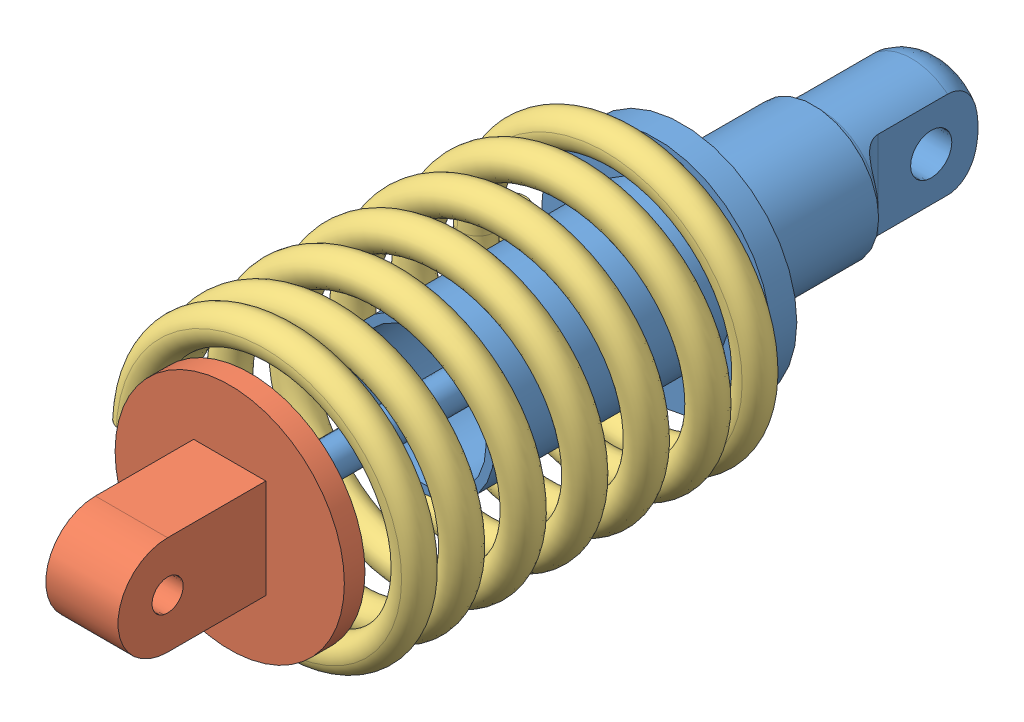
SolidWorks assembly coilover, configuration Default. Lengths in mm.
Overall size (63.59 63.59 167.73).
3 component instances, 3 part files, 4 mates.
Components (placement in the parent):
- coilover base-1: coilover base [Default] at (-107.9256 24.6681 -16.3782) size (44.45 44.45 139.07)
- coilover end-1: coilover end [Default] at (-100.9256 24.6681 115.8118) x (0 -1 0) z (-1 0 0) size (44.45 32.67 44.45)
- coil-1: coil [Default] at (-107.9256 24.6681 23.5385) size (63.59 63.59 79.45)
Mates (geometry in assembly coordinates):
- Concentric1: concentric aligned: cylinder of coilover base-1 through (-107.9256 24.6681 96.7618) axis (0 0 -1) radius 3.175; cylinder of coilover end-1 through (-107.9256 24.6681 96.7618) axis (0 0 -1) radius 3.175
- Coincident1: coincident anti-aligned: plane of coilover base-1 through (-107.9256 24.6681 96.7618) normal (0 0 1); plane of coilover end-1 through (-100.9256 24.6681 96.7618) normal (0 0 -1)
- Concentric3: concentric anti-aligned: circle of coil-1; cylinder of coilover base-1 through (-107.9256 24.6681 59.7418) axis (0 0 -1) radius 14.2875
- Coincident3: coincident aligned: plane of coilover base-1 through (-114.9256 11.9681 -16.3782) normal (-1 0 0); plane of coilover end-1 through (-114.9256 24.6681 115.8118) normal (-1 0 0)
